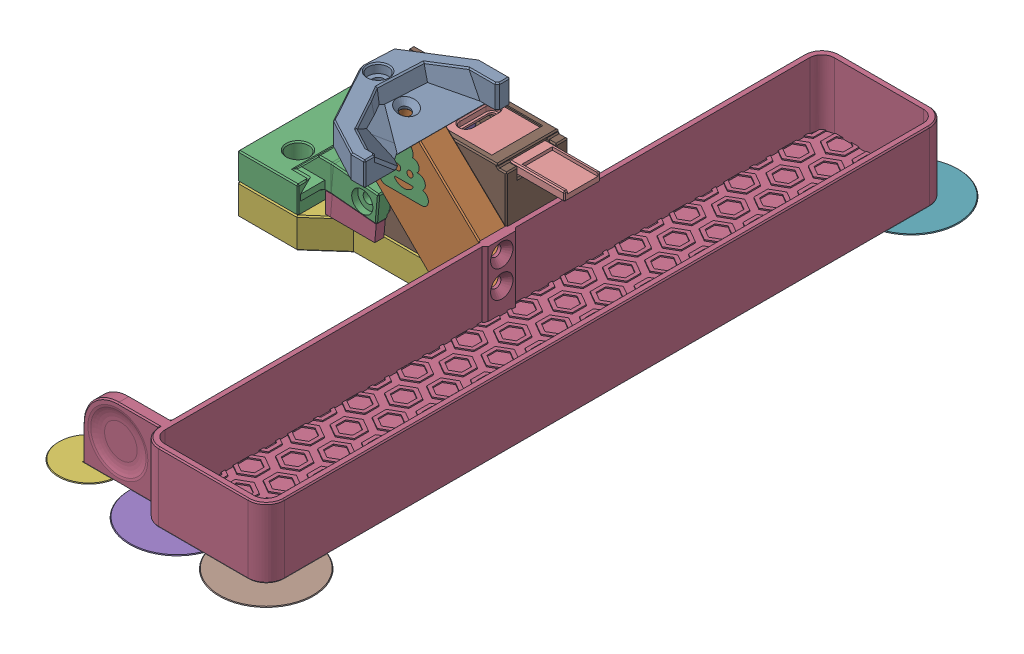
SolidWorks assembly Blobifier, configuration Default. Lengths in mm.
Overall size (131.1 60.52 244.2).
10 component instances, 8 part files, 0 mates.
Components (placement in the parent):
- Bucket Assembly-1: Bucket Assembly [Default] at origin size (93.45 50.52 244.2)
  - Shaker Stealthburner-1: Shaker Stealthburner [Default] at origin size (42.35 45.52 48.1)
    - Shaker-1: Shaker [Default] at origin size (27.97 8.5 48.1)
    - Arm-1: Arm [Default] at origin size (42.35 37.5 9)
  - Bucket-1: Bucket [Default] at origin size (86.2 23 244.2)
- Tray-1: Tray [Default] at origin size (43 3 17.8)
- Base-1: Base [Default] at origin size (50.9 39 20.4)
- Mount_voron_2.4-1: Mount_voron_2.4 [Default] at origin size (41.79 16 38)
- [a]_servo_arm_MG90S-3PS v2-1: [a]_servo_arm_MG90S-3PS v2 [Default] at (149.8223 -115.3 -212.9169) x (-0.766044 0 0.642788) z (0.642788 0 0.766044) size (12.24 5.1 13.49)
- Base shim-1: Base shim [Default] at origin size (80 10 38)
